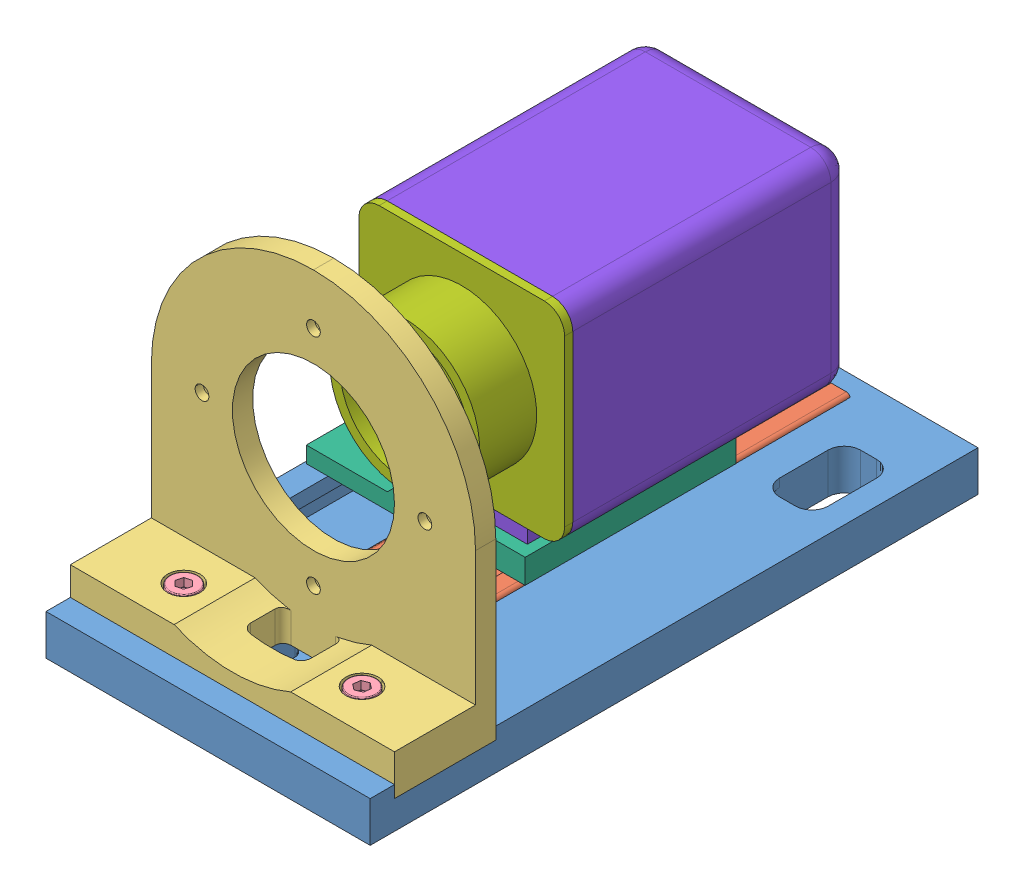
SolidWorks assembly Sistema_visao, configuration Default. Lengths in mm.
Overall size (80 99 174.57).
17 component instances, 10 part files, 33 mates.
Components (placement in the parent):
- Apoio_sistema_visao-1: Apoio_sistema_visao [Default] at (2.5288 -2.475 -3.0498) size (80 10 150)
- Calha_deslizante_27mm-1: Calha_deslizante_27mm [Default] at (2.5288 -0.475 40.9502) x (1 0 0) z (0 1 0) size (27 114 8.7)
- Apoio_iluminacaoLEDs-1: Apoio_iluminacaoLEDs [Default] at (2.5288 47.525 45.9502) size (80 83 83.14)
- Socket Head Cap Screw_ISO-1: Socket Head Cap Screw_ISO [ISO 4762 M4 x 12 --- 12C] at (-19.4712 14.525 55.9502) x (0 -1 0) z (-0.2501 0 -0.96822) size (16 7 7)
- Socket Head Cap Screw_ISO-2: Socket Head Cap Screw_ISO [ISO 4762 M4 x 12 --- 12C] at (24.5288 14.525 55.9502) x (0 -1 0) z (-0.380763 0 -0.924673) size (16 7 7)
- Carro_deslizante_27mm-1: Carro_deslizante_27mm [Default] at (2.5288 -0.525 -23.2951) x (1 0 0) z (0 1 0) size (23.9 40 5.35)
- Apoio_camara_27mm-1: Apoio_camara_27mm [Default] at (2.5288 7.975 -43.2951) x (-1 0 0) z (0 0 -1) size (54 7 52)
- Camara-1: Camara [Default] at (-7.4062 36.6309 -9.1632) size (50.8 57.8 84.8)
  - Encaixe_lente-1: Encaixe_lente [Default] at (9.935 10.7441 16.5114) size (50.8 50.8 16.1)
  - Carapaca-1: Carapaca [Default] at (9.935 10.7441 -17.8386) size (50.8 57.8 68.7)
- Socket Button Head Screw_ISO-1: Socket Button Head Screw_ISO [ISO 7380 - M6 x 10 --- 10C] at (2.5288 9.575 -1.2951) x (0 1 0) z (-0.765429 0 0.643521) size (13.3 10.5 10.5)
- Socket Button Head Screw_ISO-2: Socket Button Head Screw_ISO [ISO 7380 - M6 x 10 --- 10C] at (2.5288 9.575 -23.2951) x (0 1 0) z (0.299016 0 -0.954248) size (13.3 10.5 10.5)
- Socket Button Head Screw_ISO-3: Socket Button Head Screw_ISO [ISO 7380 - M4 x 8 --- 8C] at (2.5288 5.275 -13.2951) x (0 1 0) z (-0.212483 0 0.977165) size (10.2 7.6 7.6)
- Socket Button Head Screw_ISO-4: Socket Button Head Screw_ISO [ISO 7380 - M4 x 8 --- 8C] at (2.5288 5.275 -33.2951) x (0 1 0) z (-0.150761 0 0.98857) size (10.2 7.6 7.6)
- Socket Head Cap Screw_ISO-3: Socket Head Cap Screw_ISO [ISO 4762 M6 x 12 --- 12C] at (-28.4712 17.975 -17.2951) x (0 -1 0) z (-0.981232 0 0.192829) size (18 10 10)
- Hex Nut GradeC_ISO-1: Hex Nut GradeC_ISO [Hexagon Nut ISO - 4034 - M6 - C] at (-28.4712 4.025 -17.2951) x (1 0 0) z (0 1 0) size (10 11.55 6.1)
- Socket Button Head Screw_ISO-6: Socket Button Head Screw_ISO [ISO 7380 - M4 x 12 --- 12C] at (2.5288 2.725 10.9502) x (0 -1 0) z (0.860915 0 -0.508749) size (14.2 7.6 7.6)
Mates (geometry in assembly coordinates):
- Width1: width: plane of Apoio_sistema_visao-1 through (-10.9712 -0.475 40.9502) normal (1 0 0); plane of Apoio_sistema_visao-1 through (16.0288 -0.475 40.9502) normal (-1 0 0); plane of Calha_deslizante_27mm-1 through (16.0288 3.525 40.9502) normal (1 0 0); plane of Calha_deslizante_27mm-1 through (-10.9712 7.225 40.9502) normal (-1 0 0)
- Coincident1: coincident aligned: plane of Apoio_sistema_visao-1 through (-37.4712 4.525 40.9502) normal (0 0 1); plane of Calha_deslizante_27mm-1 through (2.5288 3.2961 40.9502) normal (0 0 1)
- Coincident2: coincident anti-aligned: plane of Apoio_sistema_visao-1 through (-10.9712 -0.475 -73.0498) normal (0 1 0); plane of Calha_deslizante_27mm-1 through (2.5288 -0.475 40.9502) normal (0 -1 0)
- Concentric1: concentric aligned: cylinder of Apoio_sistema_visao-1 through (-19.4712 4.525 55.9502) axis (0 1 0) radius 1.65; cylinder of Apoio_iluminacaoLEDs-1 through (-19.4712 14.525 55.9502) axis (0 1 0) radius 2.25
- Concentric3: concentric aligned: cylinder of Apoio_sistema_visao-1 through (24.5288 4.525 55.9502) axis (0 1 0) radius 1.65; cylinder of Apoio_iluminacaoLEDs-1 through (24.5288 14.525 55.9502) axis (0 1 0) radius 2.25
- Coincident3: coincident anti-aligned: plane of Apoio_sistema_visao-1 through (-37.4712 4.525 65.9502) normal (0 1 0); plane of Apoio_iluminacaoLEDs-1 through (-37.4712 4.525 40.9502) normal (0 -1 0)
- Concentric4: concentric aligned: cylinder of Apoio_sistema_visao-1 through (-19.4712 4.525 55.9502) axis (0 1 0) radius 1.65; cylinder of Socket Head Cap Screw_ISO-1 through (-19.4712 46.275 55.9502) axis (0 1 0) radius 2
- Concentric5: concentric aligned: cylinder of Apoio_sistema_visao-1 through (24.5288 4.525 55.9502) axis (0 1 0) radius 1.65; cylinder of Socket Head Cap Screw_ISO-2 through (24.5288 46.275 55.9502) axis (0 1 0) radius 2
- Coincident4: coincident anti-aligned: plane of Apoio_iluminacaoLEDs-1 through (-17.2212 10.525 55.9502) normal (0 1 0); plane of Socket Head Cap Screw_ISO-1 through (-22.86 10.525 56.8255) normal (0 -1 0)
- Coincident5: coincident anti-aligned: plane of Apoio_iluminacaoLEDs-1 through (26.7788 10.525 55.9502) normal (0 1 0); plane of Socket Head Cap Screw_ISO-2 through (21.2924 10.525 57.2829) normal (0 -1 0)
- Concentric6: concentric aligned: cylinder of Apoio_camara_27mm-1 through (2.5288 8.975 -1.2951) axis (0 -1 0) radius 3.5; cylinder of Camara-1/Carapaca-1 through (2.5288 14.975 -1.2951) axis (0 -1 0) radius 2.5
- Concentric7: concentric aligned: cylinder of Apoio_camara_27mm-1 through (2.5288 8.975 -23.2951) axis (0 -1 0) radius 3.5; cylinder of Camara-1/Carapaca-1 through (2.5288 14.975 -23.2951) axis (0 -1 0) radius 2.5
- Coincident6: coincident anti-aligned: plane of Apoio_camara_27mm-1 through (-16.4712 14.975 -3.2951) normal (0 1 0); plane of Camara-1/Carapaca-1 through (-9.9712 14.975 -28.3517) normal (0 -1 0)
- Concentric8: concentric aligned: cylinder of Camara-1/Carapaca-1 through (2.5288 14.975 -1.2951) axis (0 -1 0) radius 2.5; cylinder of Socket Button Head Screw_ISO-1 through (2.5288 9.575 -1.2951) axis (0 -1 0) radius 3
- Concentric9: concentric aligned: cylinder of Camara-1/Carapaca-1 through (2.5288 14.975 -23.2951) axis (0 -1 0) radius 2.5; cylinder of Socket Button Head Screw_ISO-2 through (2.5288 9.575 -23.2951) axis (0 -1 0) radius 3
- Coincident7: coincident anti-aligned: plane of Apoio_camara_27mm-1 through (-0.9712 12.875 -1.2951) normal (0 -1 0); plane of Socket Button Head Screw_ISO-1 through (0.5982 12.875 -3.5914) normal (0 1 0)
- Coincident8: coincident anti-aligned: plane of Apoio_camara_27mm-1 through (-0.9712 12.875 -23.2951) normal (0 -1 0); plane of Socket Button Head Screw_ISO-2 through (5.3915 12.875 -22.398) normal (0 1 0)
- Concentric10: concentric anti-aligned: cylinder of Carro_deslizante_27mm-1 through (2.5288 8.875 -13.2951) axis (0 1 0) radius 2.25; cylinder of Apoio_camara_27mm-1 through (2.5288 8.975 -13.2951) axis (0 -1 0) radius 1.65
- Concentric11: concentric anti-aligned: cylinder of Carro_deslizante_27mm-1 through (2.5288 8.875 -33.2951) axis (0 1 0) radius 2.25; cylinder of Apoio_camara_27mm-1 through (2.5288 8.975 -33.2951) axis (0 -1 0) radius 1.65
- Coincident9: coincident anti-aligned: plane of Carro_deslizante_27mm-1 through (9.0238 8.975 -8.2451) normal (0 1 0); plane of Apoio_camara_27mm-1 through (17.5288 8.975 -3.2951) normal (0 -1 0)
- Concentric12: concentric aligned: cylinder of Apoio_camara_27mm-1 through (2.5288 8.975 -13.2951) axis (0 -1 0) radius 1.65; cylinder of Socket Button Head Screw_ISO-3 through (2.5288 5.275 -13.2951) axis (0 -1 0) radius 2
- Concentric13: concentric aligned: cylinder of Apoio_camara_27mm-1 through (2.5288 8.975 -33.2951) axis (0 -1 0) radius 1.65; cylinder of Socket Button Head Screw_ISO-4 through (2.5288 5.275 -33.2951) axis (0 -1 0) radius 2
- Coincident10: coincident anti-aligned: plane of Carro_deslizante_27mm-1 through (5.8788 7.475 -33.2951) normal (0 -1 0); plane of Socket Button Head Screw_ISO-4 through (0.5516 7.475 -33.5966) normal (0 1 0)
- Coincident11: coincident anti-aligned: plane of Carro_deslizante_27mm-1 through (5.8788 7.475 -13.2951) normal (0 -1 0); plane of Socket Button Head Screw_ISO-3 through (0.5744 7.475 -13.7201) normal (0 1 0)
- Width2: width: plane of Calha_deslizante_27mm-1 through (14.5288 6.625 40.9502) normal (-1 0 0); plane of Calha_deslizante_27mm-1 through (-9.4712 4.125 40.9502) normal (1 0 0); plane of Carro_deslizante_27mm-1 through (14.4788 4.202 -3.2951) normal (1 0 0); plane of Carro_deslizante_27mm-1 through (-9.4212 6.448 -3.2951) normal (-1 0 0)
- Coincident12: coincident anti-aligned: plane of Calha_deslizante_27mm-1 through (14.0288 3.625 40.9502) normal (0 1 0); plane of Carro_deslizante_27mm-1 through (7.6788 3.625 -3.2951) normal (0 -1 0)
- Width3: width: plane of Apoio_sistema_visao-1 through (-23.3712 4.025 32.9502) normal (-1 0 0); plane of Apoio_sistema_visao-1 through (-33.5712 4.025 32.9502) normal (1 0 0); plane of Hex Nut GradeC_ISO-1 through (-33.4712 -2.075 -20.1818) normal (-1 0 0); plane of Hex Nut GradeC_ISO-1 through (-23.4712 -2.075 -20.1818) normal (1 0 0)
- Coincident13: coincident anti-aligned: plane of Apoio_sistema_visao-1 through (-28.4712 4.025 32.9502) normal (0 -1 0); plane of Hex Nut GradeC_ISO-1 through (-28.4712 4.025 -23.0686) normal (0 1 0)
- Concentric14: concentric aligned: cylinder of Socket Head Cap Screw_ISO-3 through (-28.4712 49.725 -17.2951) axis (0 1 0) radius 3; cylinder of Apoio_camara_27mm-1 through (-28.4712 11.975 -17.2951) axis (0 1 0) radius 3.1
- Concentric15: concentric aligned: cylinder of Apoio_camara_27mm-1 through (-28.4712 11.975 -17.2951) axis (0 1 0) radius 3.1; cylinder of Hex Nut GradeC_ISO-1 through (-28.4712 -2.075 -17.2951) axis (0 1 0) radius 2.5
- Coincident14: coincident anti-aligned: plane of Apoio_camara_27mm-1 through (-36.4712 11.975 -3.2951) normal (0 1 0); plane of Socket Head Cap Screw_ISO-3 through (-27.5071 11.975 -12.3889) normal (0 -1 0)
- Concentric17: concentric aligned: cylinder of Socket Button Head Screw_ISO-6 through (2.5288 2.725 10.9502) axis (0 1 0) radius 2; cylinder of Calha_deslizante_27mm-1 through (2.5288 0.025 10.9502) axis (0 1 0) radius 2.25
- Coincident15: coincident anti-aligned: plane of Calha_deslizante_27mm-1 through (5.7788 0.525 10.9502) normal (0 1 0); plane of Socket Button Head Screw_ISO-6 through (1.5113 0.525 9.2284) normal (0 -1 0)
